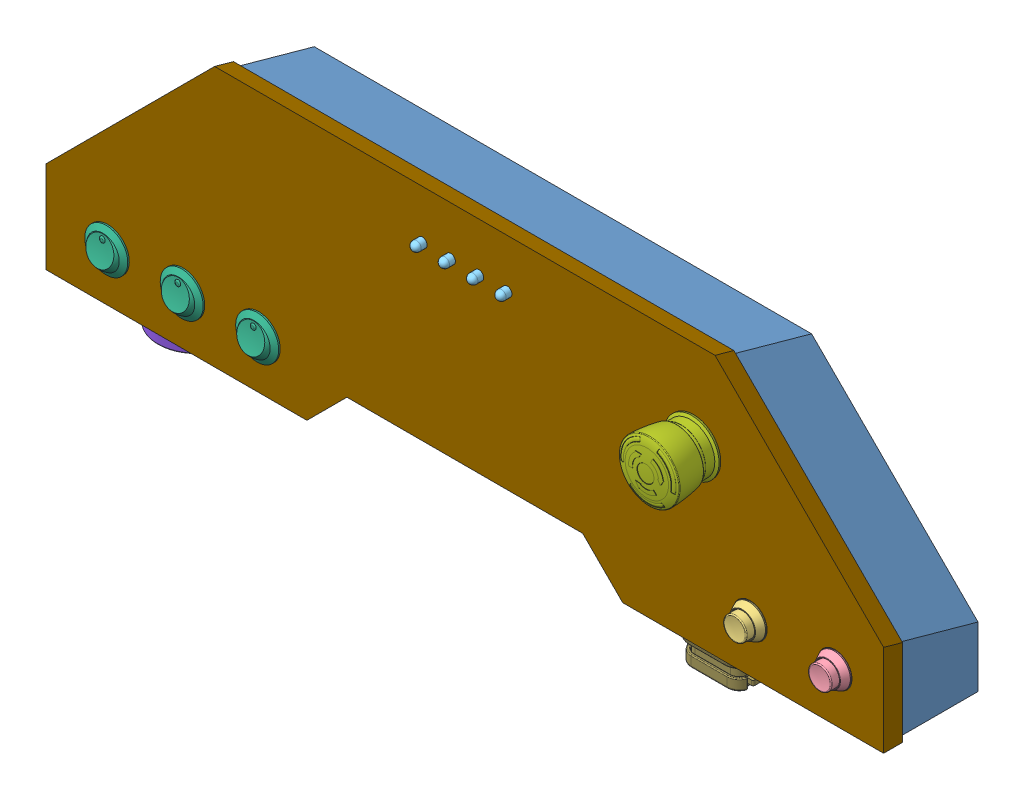
SolidWorks assembly Dashboard-topology-assembly, configuration Default. Lengths in mm.
Overall size (444 167.26 92.72).
17 component instances, 12 part files, 44 mates.
Components (placement in the parent):
- 3dprint-part-1: 3dprint-part [Default] at origin size (440 134 50)
- San_Ace_DC_52GA15_RD_Fan-1: San_Ace_DC_52GA15_RD_Fan [Default] at (-87.6831 -64.3996 -32) size (52.01 52.01 15.5)
- startbutton-1: startbutton [Default] at (151.2383 -117.629 -1.6) x (0.328448 0.944522 0) z (0.944522 -0.328448 0) size (17.4 38.38 17.4)
- startbutton2-1: startbutton2 [Default] at (196.2383 -117.629 -1.6) x (1 0 0) z (0 -1 0) size (17.4 38.38 17.4)
- led5mm!-1: led5mm! [Default] at (-22.5217 -31.109 -1) x (0.395725 0.918369 0) z (0 0 1) size (5.47 5.9 19.61)
- led5mm!-2: led5mm! [Default] at (-7.5217 -31.109 -1) x (-0.665374 0.74651 0) z (0 0 1) size (5.47 5.9 19.61)
- led5mm!-3: led5mm! [Default] at (7.4783 -31.109 -1) x (-0.609901 -0.792478 0) z (0 0 1) size (5.47 5.9 19.61)
- led5mm!-4: led5mm! [Default] at (22.4783 -31.109 -1) x (-0.433396 -0.901204 0) z (0 0 1) size (5.47 5.9 19.61)
- rockerswitch-2: rockerswitch [Default] at (-143.2317 -126.029 -12.7) x (0 1 0) z (0 0 1) size (23.3 25.94 28.82)
- rockerswitch-3: rockerswitch [Default] at (-183.2317 -126.029 -12.7) x (0 1 0) z (0 0 1) size (23.3 25.94 28.82)
- rockerswitch-4: rockerswitch [Default] at (-103.2317 -126.029 -12.7) x (0 1 0) z (0 0 1) size (23.3 25.94 28.82)
- 84-5030_0020_19017_434-1: 84-5030_0020_19017_434 [Default] at (121.2383 -52.629 2.0007) x (0.890267 0.455439 0) z (0 0 1) size (32.64 32.3 45.32)
- buzzer-1: buzzer [Default] at (-167 -136.46 -23) x (1 0 0) z (0 0 -1) size (62.28 16 41.5)
- carbonfacade-1: carbonfacade [Default] at (-0.0217 0.631 2) x (-1 0 0) z (0 -1 0) size (444 10 138)
- dash_v6-1: dash_v6 [Default] at (455.9251 -209.8079 -15.1) x (-1 0 0) z (0 0 -1) size (428.92 141.26 38.32)
- housing35pos-te-1: housing35pos-te [Default] at (0.5 -89.7368 -39.7) x (-1 0 0) z (0 0 1) size (63.4 34.6 33.8)
- 14-pos-header-1: 14-pos-header [Default] at (112.3021 -149.481 -27.3327) x (1 0 0) z (0 1 0) size (35.4 34.6 33.75)
Mates (geometry in assembly coordinates):
- Coincident1: coincident aligned: plane of 3dprint-part-1 through (0 0 0) normal (0 0 1); plane of assembly through (0 0 0) normal (0 0 1)
- Coincident2: coincident aligned: plane of 3dprint-part-1 through (0 0 0) normal (0 1 0); plane of assembly through (0 0 0) normal (0 1 0)
- Coincident3: coincident aligned: plane of 3dprint-part-1 through (0 0 0) normal (1 0 0); plane of assembly through (0 0 0) normal (1 0 0)
- Concentric5: concentric aligned: circle of 3dprint-part-1; cylinder of San_Ace_DC_52GA15_RD_Fan-1 through (-66.6831 -43.3996 -47.4647) axis (0 0 1) radius 2.25
- Concentric6: concentric anti-aligned: circle of 3dprint-part-1; circle of San_Ace_DC_52GA15_RD_Fan-1
- Coincident7: coincident anti-aligned: plane of 3dprint-part-1 through (0 0 -47) normal (0 0 1); plane of San_Ace_DC_52GA15_RD_Fan-1 through (-109.6831 -86.3996 -47) normal (0 0 -1)
- Coincident23: coincident aligned: plane of rockerswitch-3 through (-189.2817 -117.629 2) normal (0 0 -1); plane of rockerswitch-2 through (-149.2817 -117.629 2) normal (0 0 -1)
- Coincident26: coincident aligned: plane of rockerswitch-3 through (-189.2817 -117.629 2) normal (0 0 -1); plane of rockerswitch-4 through (-109.2817 -117.629 2) normal (0 0 -1)
- Concentric19: concentric aligned: cylinder of 3dprint-part-1 through (-167 -201.397 -23) axis (0 1 0) radius 21; circle of buzzer-1
- Parallel3: parallel anti-aligned: plane of 3dprint-part-1 through (0 0 0) normal (0 0 1); plane of buzzer-1 through (-167 -136.46 -23) normal (0 0 -1)
- Coincident30: coincident anti-aligned: plane of 3dprint-part-1 through (0 -141.46 0) normal (0 1 0); plane of buzzer-1 through (-167 -141.46 -23) normal (0 -1 0)
- Coincident33: coincident anti-aligned: plane of 3dprint-part-1 through (0 0 0) normal (0 0 1); plane of carbonfacade-1 through (-0.0217 0.631 0) normal (0 0 -1)
- Coincident34: coincident anti-aligned: plane of 3dprint-part-1 through (0 -7.4273 2.0623) normal (0 0.963545 -0.267547); plane of carbonfacade-1 through (-0.0217 -6.8666 4.0819) normal (0 -0.963545 0.267547)
- Coincident35: coincident anti-aligned: plane of 3dprint-part-1 through (59.6018 59.6018 -16.5496) normal (0.693859 0.693859 -0.192664); plane of carbonfacade-1 through (175.9043 -51.443 2.3853) normal (-0.693859 -0.693859 0.192664)
- Concentric20: concentric anti-aligned: circle of startbutton-1; circle of carbonfacade-1
- Coincident36: coincident anti-aligned: plane of startbutton-1 through (151.2383 -117.629 2) normal (0 0 -1); plane of carbonfacade-1 through (-0.0217 0.631 2) normal (0 0 1)
- Concentric21: concentric anti-aligned: circle of startbutton2-1; circle of carbonfacade-1
- Coincident38: coincident anti-aligned: plane of startbutton2-1 through (196.2383 -117.629 2) normal (0 0 -1); plane of carbonfacade-1 through (-0.0217 0.631 2) normal (0 0 1)
- Concentric22: concentric anti-aligned: circle of rockerswitch-3; circle of carbonfacade-1
- Concentric23: concentric anti-aligned: circle of rockerswitch-2; circle of carbonfacade-1
- Concentric24: concentric anti-aligned: circle of rockerswitch-4; circle of carbonfacade-1
- Coincident39: coincident anti-aligned: plane of rockerswitch-4 through (-109.2817 -117.629 2) normal (0 0 -1); plane of carbonfacade-1 through (-0.0217 0.631 2) normal (0 0 1)
- Concentric25: concentric anti-aligned: cylinder of led5mm!-1 through (-22.5217 -31.109 2.05) axis (0 0 1) radius 2.5; circle of carbonfacade-1
- Concentric26: concentric anti-aligned: cylinder of led5mm!-2 through (-7.5217 -31.109 2.05) axis (0 0 1) radius 2.5; circle of carbonfacade-1
- Concentric27: concentric aligned: cylinder of led5mm!-3 through (7.4783 -31.109 2.05) axis (0 0 1) radius 2.5; cylinder of carbonfacade-1 through (7.4783 -31.109 -39.1127) axis (0 0 1) radius 2.5
- Concentric28: concentric anti-aligned: cylinder of led5mm!-4 through (22.4783 -31.109 2.05) axis (0 0 1) radius 2.5; circle of carbonfacade-1
- Coincident43: coincident anti-aligned: plane of led5mm!-1 through (-22.5217 -31.109 0) normal (0 0 1); plane of carbonfacade-1 through (-0.0217 0.631 0) normal (0 0 -1)
- Coincident44: coincident anti-aligned: plane of led5mm!-2 through (-7.5217 -31.109 0) normal (0 0 1); plane of carbonfacade-1 through (-0.0217 0.631 0) normal (0 0 -1)
- Coincident45: coincident anti-aligned: plane of led5mm!-3 through (7.4783 -31.109 0) normal (0 0 1); plane of carbonfacade-1 through (-0.0217 0.631 0) normal (0 0 -1)
- Coincident46: coincident anti-aligned: plane of led5mm!-4 through (22.4783 -31.109 0) normal (0 0 1); plane of carbonfacade-1 through (-0.0217 0.631 0) normal (0 0 -1)
- Concentric29: concentric aligned: cylinder of 84-5030_0020_19017_434-1 through (121.2383 -52.629 17.8007) axis (0 0 1) radius 13; circle of carbonfacade-1
- Coincident47: coincident anti-aligned: plane of 84-5030_0020_19017_434-1 through (111.2673 -57.7299 2) normal (0 0 -1); plane of carbonfacade-1 through (-0.0217 0.631 2) normal (0 0 1)
- Concentric30: concentric aligned: cylinder of 3dprint-part-1 through (-33.2 -81.9368 35.4978) axis (0 0 -1) radius 1.65; cylinder of dash_v6-1 through (-33.2 -81.9368 -29.85) axis (0 0 -1) radius 1.085
- Parallel4: parallel anti-aligned: line of 3dprint-part-1 through (263.598 131.799 -8) axis (0 -1 0); line of dash_v6-1 through (-129.4989 -17.6219 -14.6885) axis (1 0 0)
- Coincident49: coincident anti-aligned: plane of 3dprint-part-1 through (-35 -107.7868 -29.85) normal (0 0 1); plane of dash_v6-1 through (0 -89.2368 -29.85) normal (0 0 -1)
- Coincident50: coincident: plane of dash_v6-1 through (-23.5 -77.4368 -29.1) normal (0 1 0); plane of housing35pos-te-1 through (-23 -77.4368 -40.2) normal (0 -1 0)
- Coincident51: coincident: plane of dash_v6-1 through (-29.7 -94.8368 -29.1) normal (-1 0 0); plane of housing35pos-te-1 through (-29.7 -95.3368 -40.2) normal (1 0 0)
- Coincident54: coincident anti-aligned: plane of dash_v6-1 through (0 -89.2368 -29.1) normal (0 0 -1); plane of housing35pos-te-1 through (0.5 -89.7368 -29.1) normal (0 0 1)
- Coincident55: coincident: plane of dash_v6-1 through (96.1021 -158.881 -21.2327) normal (-1 0 0); plane of 14-pos-header-1 through (96.1021 -149.981 -21.7327) normal (1 0 0)
- Coincident56: coincident: plane of dash_v6-1 through (121.3021 -158.881 -15.0327) normal (0 0 1); plane of 14-pos-header-1 through (121.8021 -149.981 -15.0327) normal (0 0 -1)
- Coincident57: coincident anti-aligned: plane of dash_v6-1 through (111.8021 -138.881 -26.8327) normal (0 -1 0); plane of 14-pos-header-1 through (112.3021 -138.881 -27.3327) normal (0 1 0)
- Parallel6: parallel anti-aligned: plane of rockerswitch-2; plane of assembly
- Parallel7: parallel anti-aligned: plane of rockerswitch-3; plane of assembly
- Parallel8: parallel anti-aligned: plane of rockerswitch-4; plane of assembly
